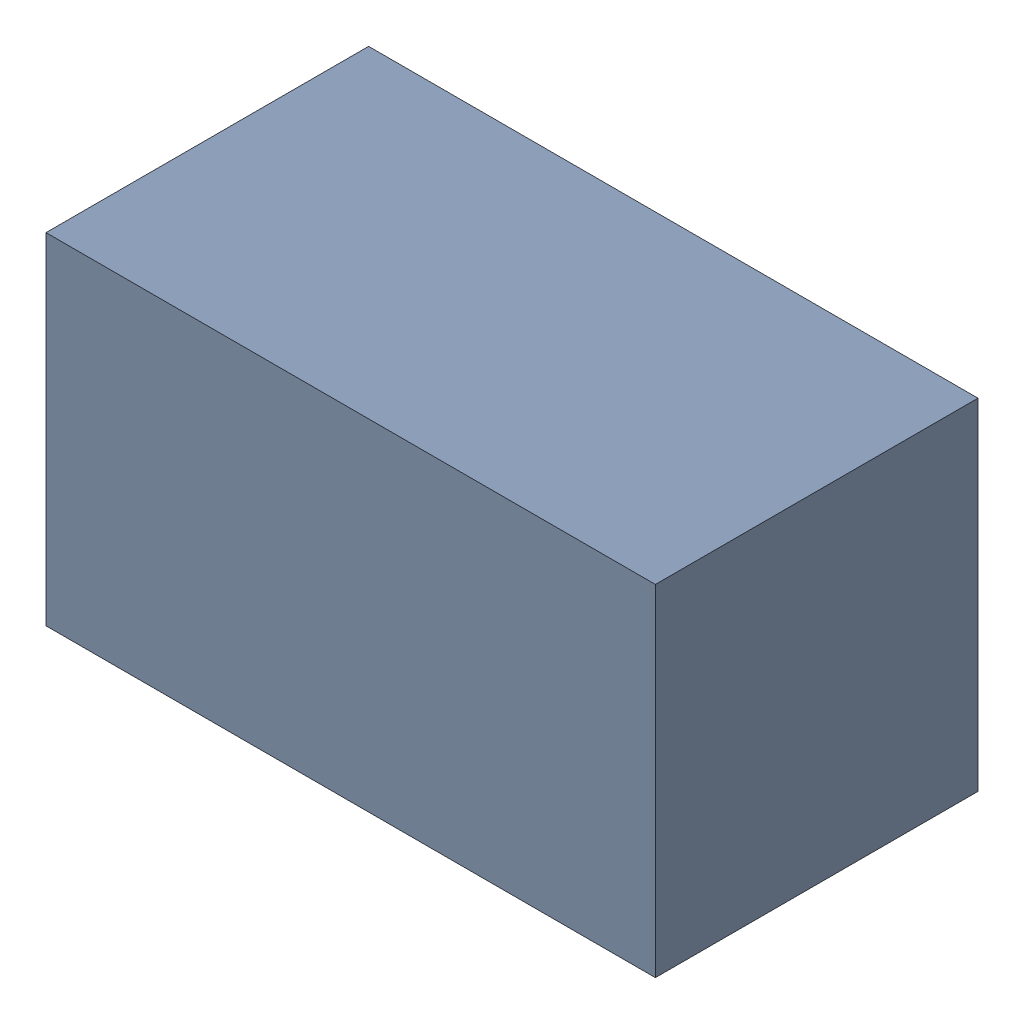
SolidWorks assembly R7, configuration Default. Lengths in mm.
Overall size (1.7 0.95 0.9).
2 component instances, 1 part files, 0 mates.
Components (placement in the parent):
- 580483600-1: 580483600 [Default] at (276.225 284.607 0) size (1.7 0.95 0.9)
  - Extruded_3-1: Extruded_3 [Default] at origin size (1.7 0.95 0.9)
